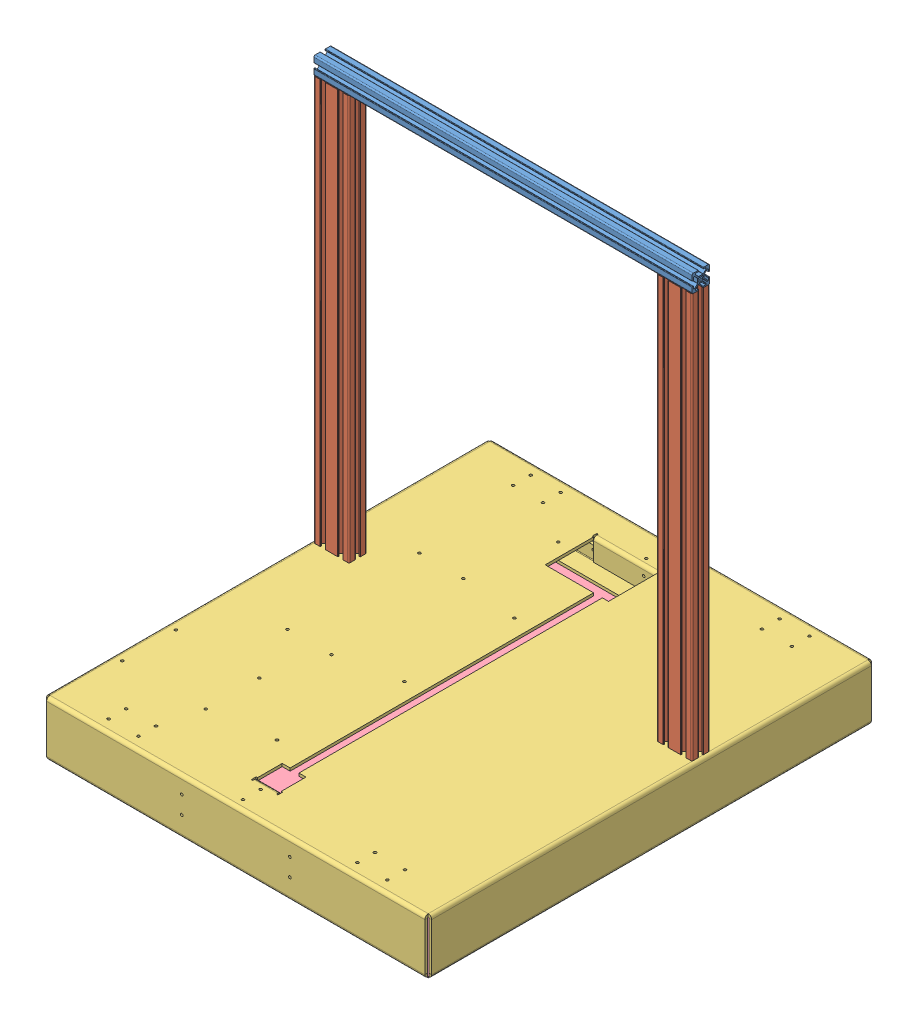
SolidWorks assembly Frame and Cover, configuration Default. Lengths in mm.
Overall size (437.82 543.39 507.82).
5 component instances, 4 part files, 12 mates.
Components (placement in the parent):
- TopCeiling-1: TopCeiling [20-2020-BLACK] at (-74.5195 587.4544 205.3802) x (0 0 -1) z (1 0 0) size (20 20 430)
- UprightSides-1: UprightSides [20-2040-BLACK] at (-84.5195 117.4544 205.3802) x (1 0 0) z (0 -1 0) size (40 20 460)
- UprightSides-2: UprightSides [20-2040-BLACK] at (-474.5195 117.4544 205.3802) x (1 0 0) z (0 -1 0) size (40 20 460)
- printer_Cover-1: printer_Cover [Default] at (-81.1195 117.4544 131.1302) size (437.82 62.09 507.82)
- bottom_Cover-1: bottom_Cover [Default] at (4575.451 55.3678 5402.6088) size (430 1.3 500)
Mates (geometry in assembly coordinates):
- Coincident17: coincident anti-aligned: plane of TopCeiling-1 through (-504.5195 577.4544 202.2422) normal (0 -1 0); plane of UprightSides-2 through (-496.9034 577.4544 201.2172) normal (0 1 0)
- Coincident18: coincident aligned: plane of TopCeiling-1 through (-504.5195 590.5924 215.3802) normal (0 0 1); plane of UprightSides-2 through (-477.6575 577.4544 215.3802) normal (0 0 1)
- Coincident19: coincident aligned: plane of TopCeiling-1 through (-504.5195 590.5924 195.8882) normal (-1 0 0); plane of UprightSides-2 through (-504.5195 577.4544 213.8802) normal (-1 0 0)
- Distance1: distance = 180 mm aligned: plane of UprightSides-1 through (-101.3815 577.4544 195.3802) normal (0 0 -1); line of printer_Cover-1 through (-74.5195 117.4544 15.3802) axis (-1 0 0)
- Coincident25: coincident anti-aligned: plane of UprightSides-1 through (-106.9034 117.4544 201.2172) normal (0 -1 0); plane of printer_Cover-1 through (-81.1195 117.4544 131.1302) normal (0 1 0)
- Coincident27: coincident anti-aligned: line of UprightSides-1 through (-74.5195 117.4544 208.5182) axis (0 0 1); line of printer_Cover-1 through (-74.5195 117.4544 515.3802) axis (0 0 -1)
- Coincident28: coincident aligned: plane of TopCeiling-1 through (-504.5195 584.3164 215.3802) normal (0 0 1); plane of UprightSides-1 through (-87.6575 577.4544 215.3802) normal (0 0 1)
- Coincident30: coincident anti-aligned: plane of TopCeiling-1 through (-504.5195 577.4544 202.2422) normal (0 -1 0); plane of UprightSides-1 through (-106.9034 577.4544 201.2172) normal (0 1 0)
- Coincident31: coincident aligned: plane of TopCeiling-1 through (-74.5195 590.5924 195.8882) normal (1 0 0); plane of UprightSides-1 through (-74.5195 577.4544 196.8802) normal (1 0 0)
- Coincident32: coincident anti-aligned: plane of printer_Cover-1 through (-81.1195 55.3678 131.1302) normal (0 -1 0); plane of bottom_Cover-1 through (4575.451 55.3678 5402.6088) normal (0 1 0)
- Coincident37: coincident aligned: plane of printer_Cover-1 through (-508.4311 59.2794 15.3507) normal (0 0 -1); plane of bottom_Cover-1 through (-504.549 54.0768 15.3507) normal (0 0 -1)
- Coincident38: coincident aligned: plane of printer_Cover-1 through (-504.549 114.2794 11.4686) normal (-1 0 0); plane of bottom_Cover-1 through (-504.549 54.0768 15.3507) normal (-1 0 0)
